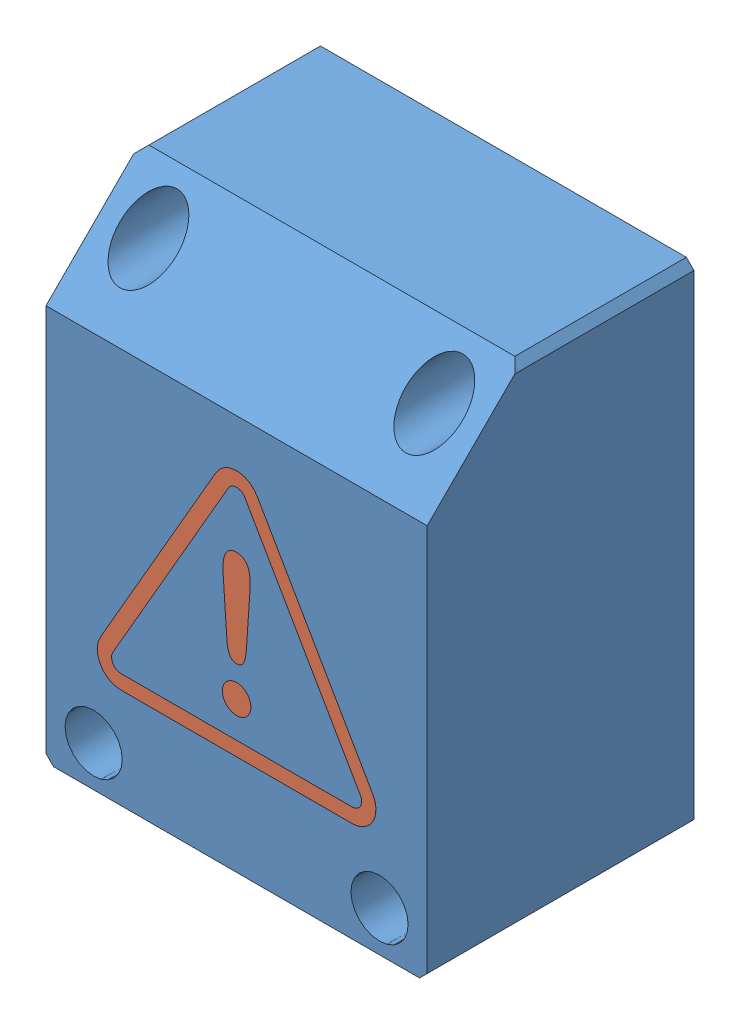
SolidWorks assembly Tool-Changer Cover Body Asm_1.0, configuration Default. Lengths in mm.
Overall size (40 51.5 28).
2 component instances, 2 part files, 4 mates.
Components (placement in the parent):
- Tool-Changer Cover Body_1.1-1: Tool-Changer Cover Body_1.1 [No Slots] at (-29.9991 0.055 1.9944) size (40 51.5 28)
- Caution Label^Tool-Changer Cover Body Asm_1.0-1: Caution Label^Tool-Changer Cover Body Asm_1.0 [Default] at (-29.9991 0.055 29.9742) size (29.25 26 0.5) (virtual)
Mates (geometry in assembly coordinates):
- InPlace1: in place: plane of Tool-Changer Cover Body_1.1-1 through (-50.1382 15.6459 29.9742) normal (0 0 1); plane of ? through (0 0 29.9742) normal (0 0 1); moOrthogonalPlaneRef_w of Tool-Changer Cover Body_1.1-1 through (-50.1382 15.6459 29.9742) normal (0 0 1); plane of ? through (0 0 29.9742) normal (0 1 0); plane of Tool-Changer Cover Body_1.1-1 through (-50.1382 15.6459 29.9742) normal (0 0 1); plane of ? through (0 0 29.9742) normal (1 0 0); plane of Tool-Changer Cover Body_1.1-1 through (-50.1382 15.6459 29.9742) normal (0 0 1); unknown of Caution Label^Tool-Changer Cover Body Asm_1.0-1
- Coincident1: coincident aligned: plane of Tool-Changer Cover Body_1.1-1; plane of Caution Label^Tool-Changer Cover Body Asm_1.0-1
- Coincident2: coincident aligned: moOrthogonalPlaneRef_w of Tool-Changer Cover Body_1.1-1 through (-29.9991 0.055 29.9742) normal (0 1 0); plane of Caution Label^Tool-Changer Cover Body Asm_1.0-1 through (-29.9991 0.055 29.9742) normal (0 1 0)
- Coincident3: coincident anti-aligned: moOrthogonalPlaneRef_w of Tool-Changer Cover Body_1.1-1 through (-29.9991 0.055 29.9742) normal (-1 0 0); plane of Caution Label^Tool-Changer Cover Body Asm_1.0-1 through (-29.9991 0.055 29.9742) normal (1 0 0)
